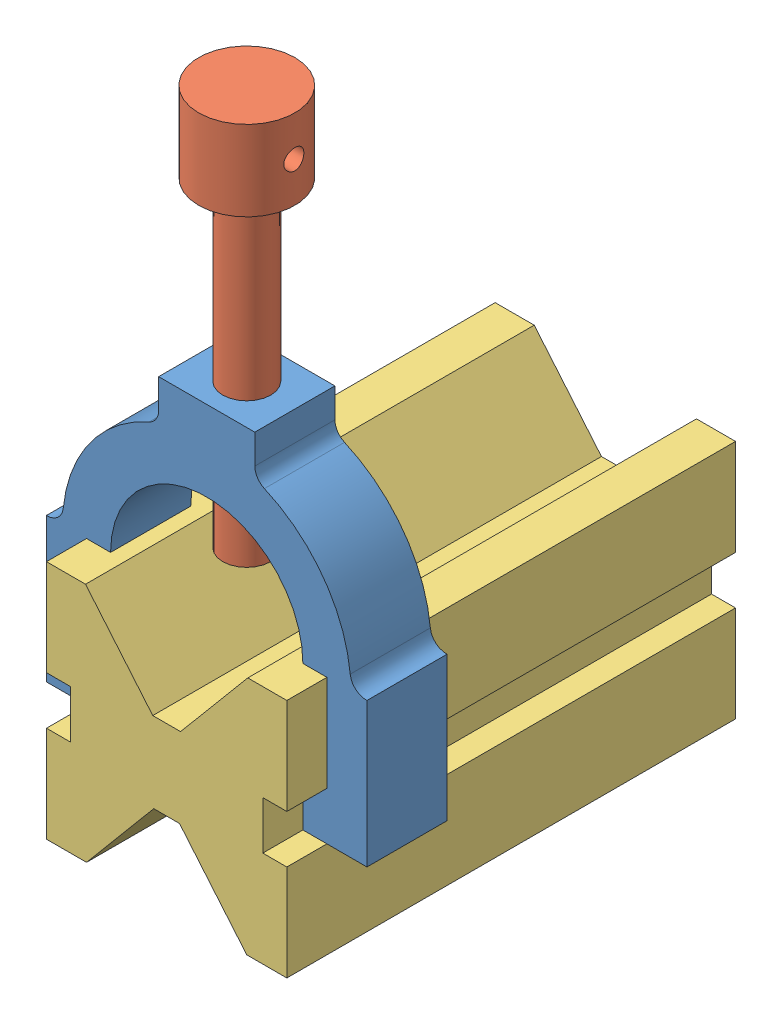
SolidWorks assembly hw06.3, configuration Default. Lengths in mm.
Overall size (2032 4267.2 2844.8).
3 component instances, 3 part files, 7 mates.
Components (placement in the parent):
- hw06.3.clamp-1: hw06.3.clamp [Default] at (762 609.6 -508) size (2032 2032 508)
- hw06.3.mallet-1: hw06.3.mallet [Default] at (762 4267.2 -508) size (609.6 2540 609.6)
- hw06.3.x-1: hw06.3.x [Default] at (762 762 -2844.8) size (1524 1524 2844.8)
Mates (geometry in assembly coordinates):
- Coincident2: coincident anti-aligned: plane of hw06.3.clamp-1 through (1371.6 609.6 -251.46) normal (-1 0 0); plane of hw06.3.x-1
- Coincident4: coincident aligned: circle of hw06.3.clamp-1; cylinder of hw06.3.mallet-1 through (762 1727.2 -508) axis (0 1 0) radius 152.4
- Distance2: distance = 1625.6 mm aligned: plane of hw06.3.clamp-1 through (457.2 2641.6 -254) normal (0 1 0); plane of hw06.3.mallet-1 through (762 4267.2 -508) normal (0 1 0)
- Coincident8: coincident anti-aligned: plane of hw06.3.clamp-1 through (1371.6 609.6 -251.46) normal (-1 0 0); plane of hw06.3.x-1 through (1371.6 914.4 0) normal (1 0 0)
- Coincident9: coincident anti-aligned: plane of hw06.3.clamp-1 through (1778 609.6 -251.46) normal (0 -1 0); plane of hw06.3.x-1 through (1371.6 609.6 0) normal (0 1 0)
- Parallel4: parallel anti-aligned: line of hw06.3.clamp-1 through (1066.8 2641.6 -759.46) axis (-1 0 0); cylinder of hw06.3.mallet-1 through (457.2 4013.2 -505.46) axis (1 0 0) radius 63.5
- Distance6: distance = 254 mm aligned: plane of hw06.3.clamp-1 through (355.6 2455.1794 -254) normal (0 0 1); plane of hw06.3.x-1 through (762 762 0) normal (0 0 1)
